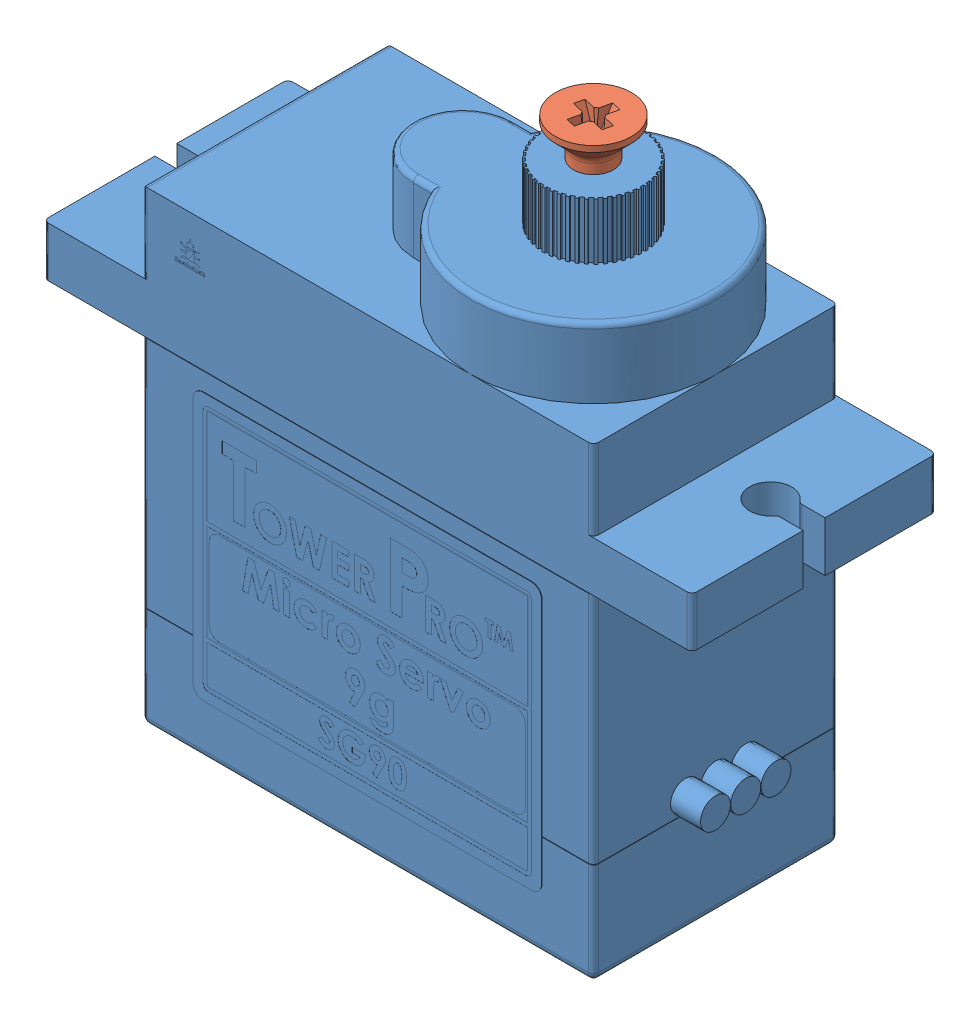
SolidWorks assembly User Library-SG90-1, configuration Default. Lengths in mm.
Overall size (32.36 31.5 12.25).
2 component instances, 2 part files, 0 mates.
Components (placement in the parent):
- User Library-SG90-1_SG90-1: User Library-SG90-1_SG90 [Default] at (9.6466 6.4738 26.0604) size (32.36 29.6 12.25)
- User Library-SG90-1_cr flat head screw_is(IS 7485 - M2 x 3 - Z -- 3N)-1: User Library-SG90-1_cr flat head screw_is(IS 7485 - M2 x 3 - Z -- 3N) [Default] at (3.5466 14.6698 32.1604) x (0 -1 0) z (-0.223757 0 0.974645) size (3 3.8 3.8)
